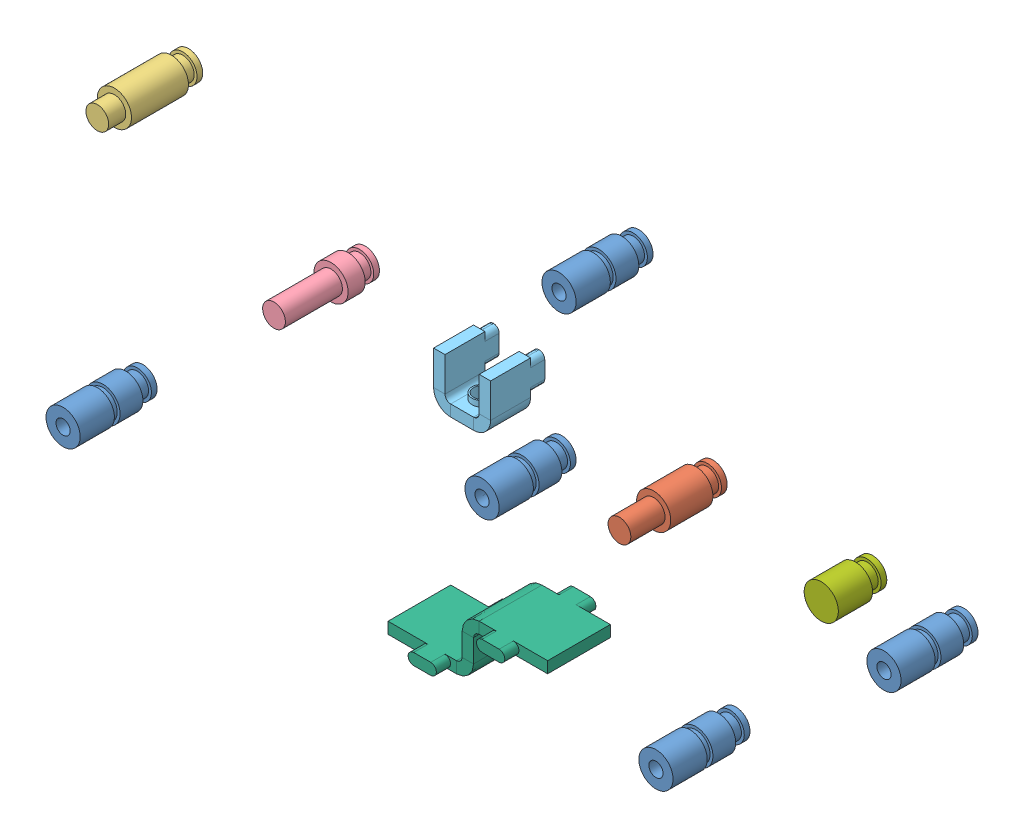
SolidWorks assembly Assemblage5, configuration Défaut. Lengths in mm.
Overall size (150 70 16.5).
11 component instances, 7 part files, 0 mates.
Components (placement in the parent):
- Pièce20-1: Pièce20 [Défaut] at (81.7227 21.0405 -3.5) x (0 0 1) z (-1 0 0) size (14 6 6)
- Pièce20-2: Pièce20 [Défaut] at (41.7227 -13.9595 -3.5) x (0 0 1) z (-1 0 0) size (14 6 6)
- Pièce20-3: Pièce20 [Défaut] at (24.7227 50.0405 -3.5) x (0 0 1) z (-1 0 0) size (14 6 6)
- Pièce20-4: Pièce20 [Défaut] at (11.2227 11.9905 -3.5) x (0 0 1) z (-0.071229 0.99746 0) size (14 6 6)
- Pièce20-5: Pièce20 [Défaut] at (-62.2773 -13.9595 -3.5) x (0 0 1) z (-1 0 0) size (14 6 6)
- Pièce21-1: Pièce21 [Défaut] at (37.7227 21.5405 -3.5) x (0 0 1) z (-1 0 0) size (16.4 6 6)
- Pièce23-1: Pièce23 [Défaut] at (-54.2773 38.0405 -3.5) x (0 0 1) z (-1 0 0) size (16 6 6)
- Pièce22-2: Pièce22 [Défaut] at (-23.2773 23.5405 -3.5) x (0 0 1) z (-0.988921 -0.148442 0) size (16 6 6)
- Pièce24-1: Pièce24 [Défaut] at (3.7227 19.5405 3) x (-1 0 0) z (0 0 -1) size (10 9 9.5)
- Pièce25-1: Pièce25 [Défaut] at (-74.2773 -20.9595 -0.5) size (28 10 16)
- Pièce38-1: Pièce38 [Défaut] at (65.7227 21.0405 -3.5) x (0 0 1) z (-1 0 0) size (9 6 6)
